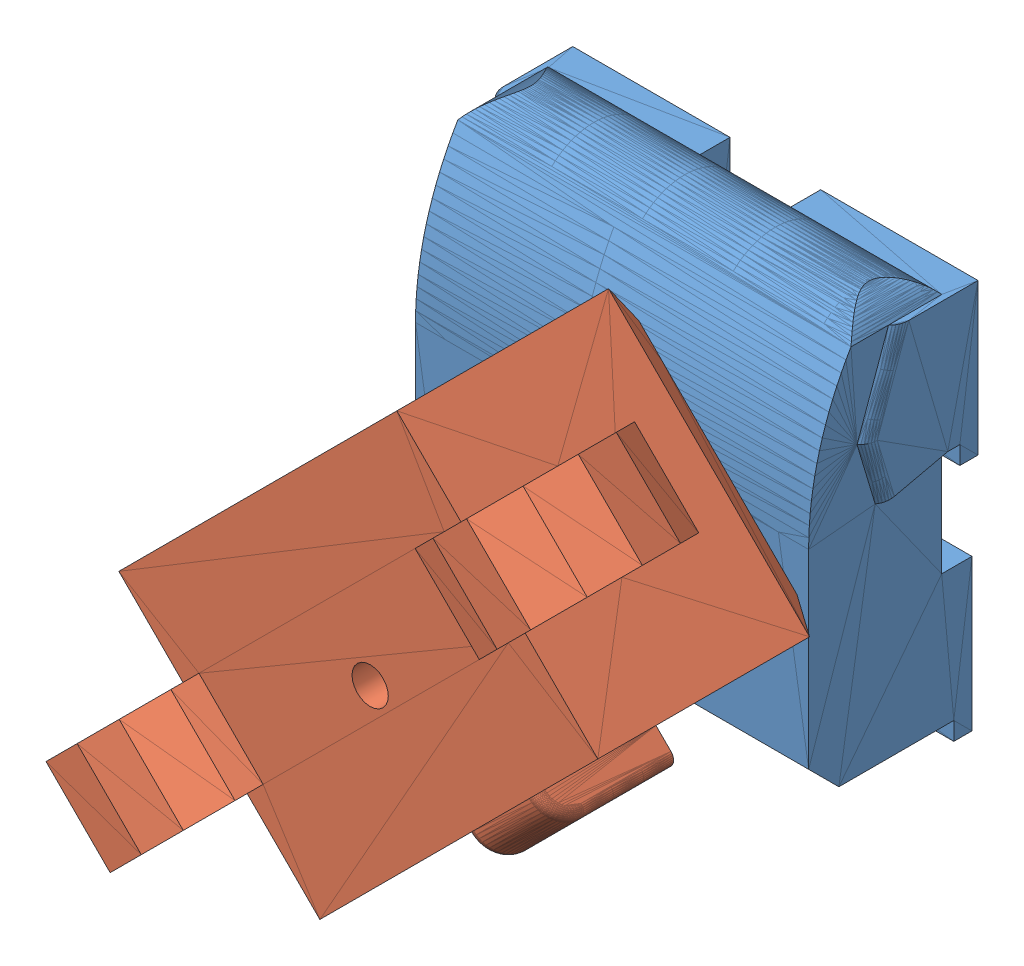
SolidWorks assembly done, configuration Default. Lengths in mm.
Overall size (119.64 119.64 78).
2 component instances, 2 part files, 4 mates.
Components (placement in the parent):
- testttt-2: testttt [Default] at (-26.1813 -106.835 25.1044) size (67 68.39 27)
- koala head-2: koala head [Default] at (25.1263 -133.2173 25.1044) x (0.707107 0.707107 0) z (0 0 1) size (117.2 52 55)
Mates (geometry in assembly coordinates):
- Coincident19: coincident anti-aligned: line of koala body-2 through (41.8187 -50.3497 46.1773) axis (0 0 1); line of koala head-2 through (41.8187 -50.3497 67.1044) axis (0 0 -1)
- Coincident20: coincident anti-aligned: line of testttt-2 through (23.8187 -50.3497 44.9576) axis (0 0 1); line of koala head-2 through (23.8187 -50.3497 67.1044) axis (0 0 -1)
- Parallel12: parallel aligned: line of koala body-2 through (31.3187 -58.2003 48.1044) axis (0 0 1); line of koala head-2 through (31.3187 -58.0924 48.1044) axis (0 0 1)
- Coincident22: coincident anti-aligned: plane of koala body-2 through (-26.1813 -106.835 48.1044) normal (0 0 1); plane of koala head-2 through (25.1263 -133.2173 48.1044) normal (0 0 -1)
